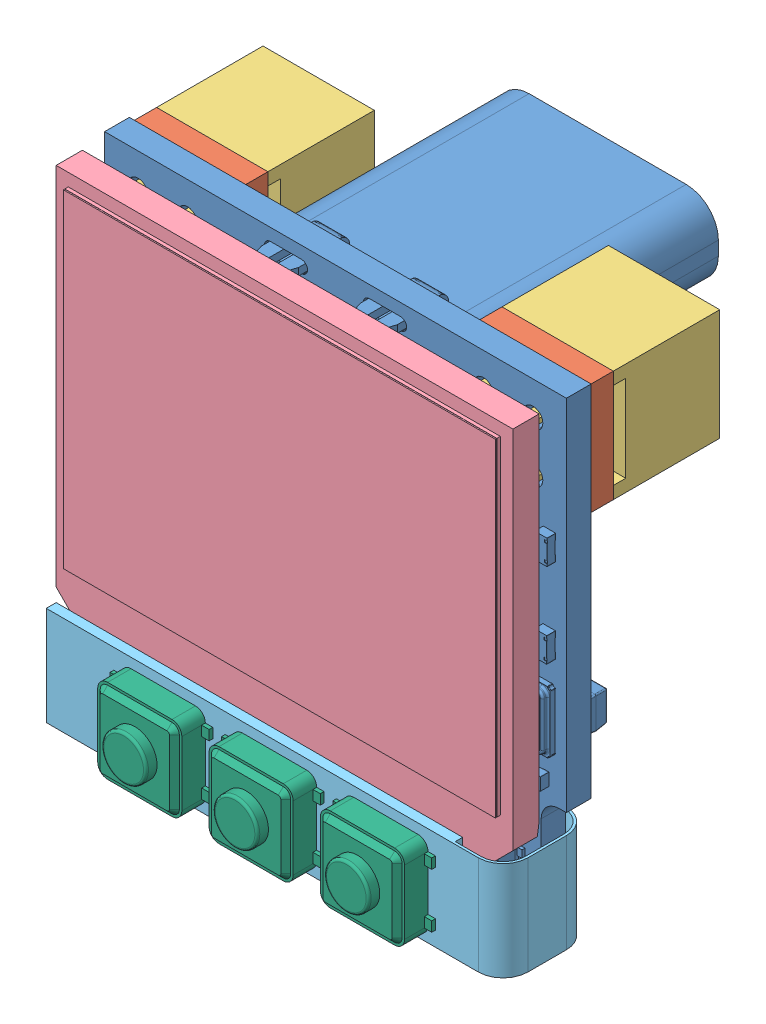
SolidWorks assembly SAU-G0_PCB, configuration 默认. Lengths in mm.
Overall size (20.36 19.5 15.06).
11 component instances, 6 part files, 12 mates.
Components (placement in the parent):
- SAU-G0_STEP_AD-1: SAU-G0_STEP_AD [默认] at (-16.5787 -13.328 24.4103) size (18.66 19.5 12.19)
- 2.00mm_2x2_垫板PCB_厚1.0mm-1: 2.00mm_2x2_垫板PCB_厚1.0mm [默认] at (3.1013 6.262 22.4106) x (1 0 0) z (0 -1 0) size (4.5 1 4.5)
- 2.00mm母座2x2-1: 2.00mm母座2x2 [Default] at (4.1013 6.262 18.1106) x (1 0 0) z (0 1 0) size (4.5 7.1 4.5)
- 2.00mm_2x2_垫板PCB_厚1.0mm-2: 2.00mm_2x2_垫板PCB_厚1.0mm [默认] at (-10.8587 6.262 22.4106) x (-1 0 0) z (0 1 0) size (4.5 1 4.5)
- 2.00mm母座2x2-2: 2.00mm母座2x2 [Default] at (-11.8587 6.262 18.1106) x (-1 0 0) z (0 -1 0) size (4.5 7.1 4.5)
- 0.66寸_64x48_TOP_FPC背面距离背板1mm-1: 0.66寸_64x48_TOP_FPC背面距离背板1mm [Default] at (-3.8787 8.514 25.9703) x (1 0 0) z (0 -1 0) size (18.46 2.27 19.3)
- 轻触开关+柔性PCB-1: 轻触开关+柔性PCB [默认] at (-0.958 10.42 26.3367) x (1 0 0) z (0 -1 0) size (20.26 5.16 4.01)
  - 方案2-轻触开关_柔性PCB-1: 方案2-轻触开关_柔性PCB [默认] at (-12.1506 0.4339 17.21) size (20.26 3.56 4.01)
  - 轻触开关3x3.5x1.5_3x4.0x2.0-1: 轻触开关3x3.5x1.5_3x4.0x2.0 [默认] at (-2.9206 0.5339 19.31) size (4 1.6 3.4)
  - 轻触开关3x3.5x1.5_3x4.0x2.0-2: 轻触开关3x3.5x1.5_3x4.0x2.0 [默认] at (1.5794 0.5339 19.31) size (4 1.6 3.4)
  - 轻触开关3x3.5x1.5_3x4.0x2.0-3: 轻触开关3x3.5x1.5_3x4.0x2.0 [默认] at (-7.4206 0.5339 19.31) size (4 1.6 3.4)
Mates (geometry in assembly coordinates):
- 重合1: coincident anti-aligned: plane of SAU-G0_STEP_AD-1 through (-13.2107 -10.89 23.4106) normal (0 0 -1); plane of 2.00mm_2x2_垫板PCB_厚1.0mm-1 through (3.1013 6.262 23.4106) normal (0 0 1)
- 同心1: concentric aligned: cylinder of SAU-G0_STEP_AD-1 through (4.1013 5.262 23.4106) axis (0 0 -1) radius 0.4; cylinder of 2.00mm_2x2_垫板PCB_厚1.0mm-1 through (4.1013 5.262 23.4106) axis (0 0 -1) radius 0.4
- 同心2: concentric: cylinder of SAU-G0_STEP_AD-1 through (2.1013 7.262 23.4106) axis (0 0 -1) radius 0.4; cylinder of 2.00mm_2x2_垫板PCB_厚1.0mm-1 through (2.1013 7.262 23.4106) axis (0 0 -1) radius 0.4
- 重合2: coincident aligned: plane of 2.00mm_2x2_垫板PCB_厚1.0mm-1 through (5.3513 4.012 23.4106) normal (1 0 0); plane of 2.00mm母座2x2-1 through (5.3513 6.262 18.1106) normal (1 0 0)
- 重合3: coincident: plane of 2.00mm_2x2_垫板PCB_厚1.0mm-1 through (3.1013 6.262 22.4106) normal (0 0 -1); plane of 2.00mm母座2x2-1 through (5.1013 8.512 22.4106) normal (0 0 1)
- 重合4: coincident aligned: plane of 2.00mm_2x2_垫板PCB_厚1.0mm-1 through (0.8513 8.512 23.4106) normal (0 1 0); plane of 2.00mm母座2x2-1 through (5.1013 8.512 18.1106) normal (0 1 0)
- 重合5: coincident aligned: plane of 0.66寸_64x48_TOP_FPC背面距离背板1mm-1 through (-3.8787 8.514 25.9703) normal (1 0 0); plane of assembly through (-3.8787 0 0) normal (1 0 0)
- 距离1: distance = 0.1 mm aligned: plane of 0.66寸_64x48_TOP_FPC背面距离背板1mm-1 through (-3.8787 8.514 26.4703) normal (0 1 0); plane of SAU-G0_STEP_AD-1 through (-13.2107 8.614 23.4106) normal (0 1 0)
- 距离2: distance = 1 mm anti-aligned: plane of 0.66寸_64x48_TOP_FPC背面距离背板1mm-1 through (-3.8787 8.514 25.4103) normal (0 0 -1); plane of SAU-G0_STEP_AD-1 through (-13.2107 -10.89 24.4103) normal (0 0 1)
- 重合8: coincident anti-aligned: plane of SAU-G0_STEP_AD-1 through (-13.2107 -10.89 23.4106) normal (0 0 -1); plane of 轻触开关+柔性PCB-1/方案2-轻触开关_柔性PCB-1 through (4.3563 -10.79 23.4106) normal (0 0 1)
- 重合9: coincident aligned: plane of 轻触开关+柔性PCB-1 through (-3.8787 10.42 26.3367) normal (1 0 0); plane of assembly through (-3.8787 0 0) normal (1 0 0)
- 距离3: distance = 0.1 mm aligned: plane of 轻触开关+柔性PCB-1/方案2-轻触开关_柔性PCB-1 through (4.3563 -10.79 25.8706) normal (0 -1 0); plane of SAU-G0_STEP_AD-1 through (4.4323 -10.89 23.4106) normal (0 -1 0)
